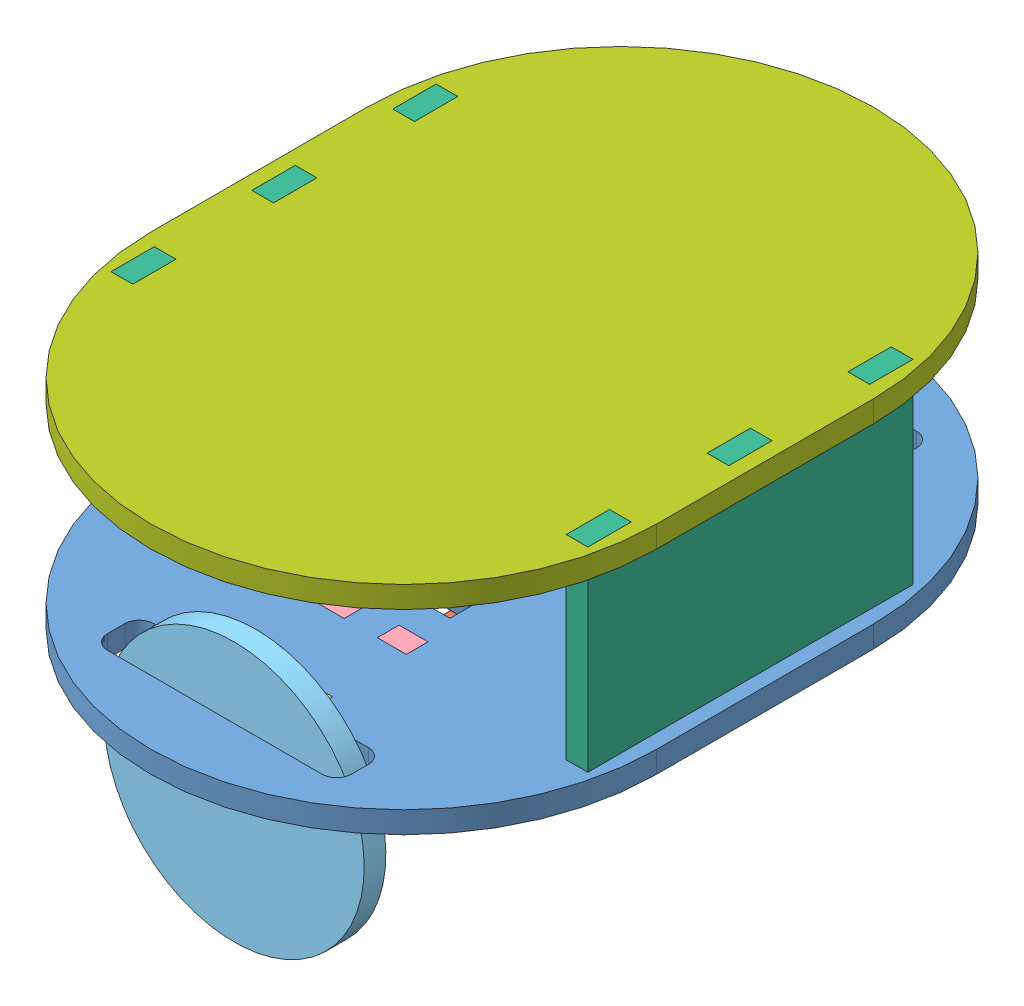
SolidWorks assembly 167BotAssembled, configuration Default. Lengths in mm.
Overall size (177.8 159.92 254).
12 component instances, 7 part files, 20 mates.
Components (placement in the parent):
- PlatformBase-1: PlatformBase [Default] at origin size (177.8 7.62 254)
- DCMotor-1: DCMotor [Default] at (0.002 -20 -50.3832) x (-0.96201 -0.273015 0) z (0.273015 -0.96201 0) size (25 85.4 25)
- MotorHolder1-1: MotorHolder1 [Default] at (-15.998 -20 -124.7832) x (1 0 0) z (0 -1 0) size (32 7.62 43.62)
- MotorHolder2-1: MotorHolder2 [Default] at (16.002 -20 -83.6352) x (-1 0 0) z (0 -1 0) size (32 7.62 43.62)
- MotorHolder1-2: MotorHolder1 [Default] at (-16.002 -20 40.9632) x (1 0 0) z (0 -1 0) size (32 7.62 43.62)
- DCMotor-2: DCMotor [Default] at (-0.002 -20 -25.8168) x (0.174286 -0.984695 0) z (-0.984695 -0.174286 0) size (25 85.4 25)
- MotorHolder2-2: MotorHolder2 [Default] at (15.998 -20 15.0552) x (-1 0 0) z (0 -1 0) size (32 7.62 43.62)
- Wheels-1: Wheels [Default] at (0.002 -20 -135.7832) x (-0.017575 -0.999846 0) z (-0.999846 0.017575 0) size (91.44 7.62 91.44)
- Wheels-2: Wheels [Default] at (-0.002 -20 59.5832) x (-0.576705 0.816953 0) z (-0.816953 -0.576705 0) size (91.44 7.62 91.44)
- Front&BackWalls-1: Front&BackWalls [Default] at (-76.2 0 -95.25) x (0 0 1) z (0 -1 0) size (114.3 7.62 76.2)
- Front&BackWalls-2: Front&BackWalls [Default] at (83.82 0 -95.25) x (0 0 1) z (0 -1 0) size (114.3 7.62 76.2)
- Platform-1: Platform [Default] at (0 68.58 0) size (177.8 7.62 254)
Mates (geometry in assembly coordinates):
- Coincident1: coincident: line of PlatformBase-1 through (16.002 7.62 -117.1632) axis (-1 0 0); line of MotorHolder1-1 through (5.842 7.62 -117.1632) axis (1 0 0)
- Coincident2: coincident: point of PlatformBase-1; point of MotorHolder1-1
- Concentric1: concentric: cylinder of DCMotor-1 through (0.002 -20 -97.3832) axis (0 0 1) radius 12.2; cylinder of MotorHolder2-1 through (0.002 -20 -91.2552) axis (0 0 1) radius 12.2
- Coincident4: coincident: point of PlatformBase-1; point of MotorHolder2-1
- Coincident9: coincident: line of PlatformBase-1 through (-16.002 7.62 48.5832) axis (0 0 -1); line of MotorHolder1-2 through (-16.002 7.62 40.9632) axis (0 0 1)
- Coincident10: coincident: line of PlatformBase-1 through (-16.002 7.62 40.9632) axis (1 0 0); line of MotorHolder1-2 through (-5.842 7.62 40.9632) axis (-1 0 0)
- Coincident11: coincident: circle of MotorHolder1-2; circle of DCMotor-2
- Coincident17: coincident: line of PlatformBase-1 through (16.002 7.62 7.4352) axis (-1 0 0); line of MotorHolder2-2 through (15.998 7.62 7.4352) axis (-1 0 0)
- Coincident20: coincident: circle of DCMotor-2; circle of Wheels-2
- Concentric4: concentric: cylinder of DCMotor-1 through (0.002 -20 -135.7832) axis (0 0 1) radius 2; cylinder of Wheels-1 through (0.002 -20 -128.1632) axis (0 0 -1) radius 2
- Coincident23: coincident: circle of DCMotor-1; circle of MotorHolder1-1
- Coincident24: coincident: circle of DCMotor-1; circle of Wheels-1
- Coincident37: coincident: point of PlatformBase-1; point of Front&BackWalls-1
- Coincident38: coincident: point of PlatformBase-1; point of Front&BackWalls-1
- Coincident39: coincident: line of PlatformBase-1 through (-83.82 0 19.05) axis (1 0 0); line of Front&BackWalls-1 through (-83.82 0 19.05) axis (1 0 0)
- Coincident40: coincident: point of PlatformBase-1; point of Front&BackWalls-2
- Coincident41: coincident: point of PlatformBase-1; point of Front&BackWalls-2
- Coincident42: coincident: point of PlatformBase-1; point of Front&BackWalls-2
- Coincident43: coincident: point of Front&BackWalls-2; point of Platform-1
- Coincident44: coincident: line of Front&BackWalls-1 through (-83.82 76.2 -95.25) axis (0 0 1); line of Platform-1 through (-83.82 76.2 -95.25) axis (0 0 1)
